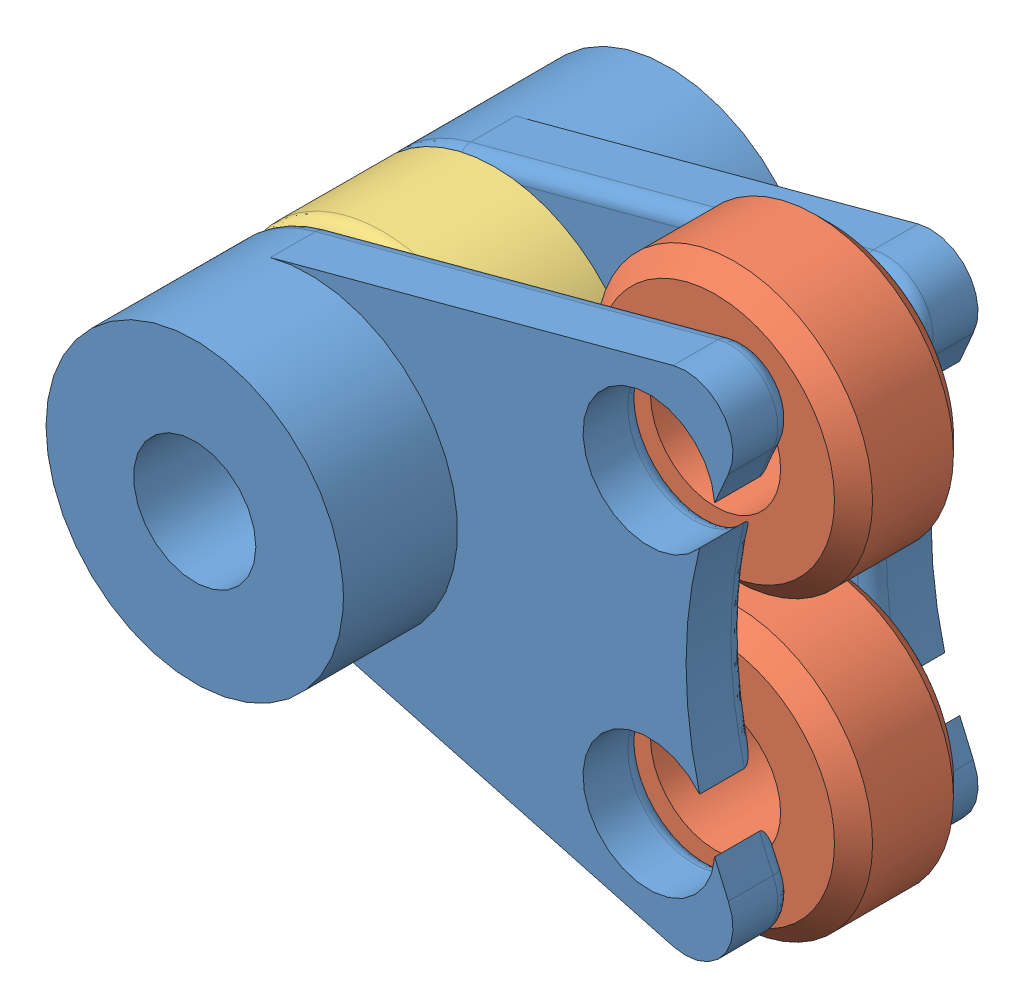
SolidWorks assembly RollerUnit, configuration Default. Lengths in mm.
Overall size (32.43 29.25 25.27).
5 component instances, 3 part files, 11 mates.
Components (placement in the parent):
- BeltRollerHolder-1: BeltRollerHolder [Default] at (6.1615 25.2155 19.6382) size (31.33 29.25 9.33)
- BeltRollerHolder-2: BeltRollerHolder [Default] at (6.1615 25.2155 32.7192) x (1 0 0) z (0 0 -1) size (31.33 29.25 9.33)
- 0.5Roller-2: 0.5Roller [Default] at (24.3085 33.153 22.8132) x (1 0 0) z (0 -1 0) size (12.7 6.35 12.7)
- 0.5Roller-3: 0.5Roller [Default] at (24.3085 17.278 22.8132) x (1 0 0) z (0 -1 0) size (12.7 6.35 12.7)
- BeltRollerHolderSpacer-1: BeltRollerHolderSpacer [Default] at (6.1615 25.2155 29.5442) x (1 0 0) z (0 1 0) size (15.88 6.73 15.88)
Mates (geometry in assembly coordinates):
- Concentric1: concentric anti-aligned: cylinder of BeltRollerHolder-2 through (25.0411 35.1495 29.3537) axis (0 0 -1) radius 1.7272; cylinder of ? through (25.0411 35.1495 28.9727) axis (0 0 1) radius 2.1526
- Concentric2: concentric anti-aligned: cylinder of BeltRollerHolder-2 through (24.3085 33.153 32.7192) axis (0 0 -1) radius 3.5179; cylinder of 0.5Roller-2 through (24.3085 33.153 29.1632) axis (0 0 1) radius 3.475
- Concentric3: concentric anti-aligned: cylinder of BeltRollerHolder-2 through (24.3085 17.278 32.7192) axis (0 0 -1) radius 3.5179; cylinder of 0.5Roller-3 through (24.3085 17.278 29.1632) axis (0 0 1) radius 3.475
- Coincident3: coincident aligned: plane of ? through (25.0411 35.1495 22.6227) normal (0 0 -1); plane of 0.5Roller-2 through (24.8758 34.7405 22.6227) normal (0 0 -1)
- Coincident4: coincident aligned: plane of 0.5Roller-2 through (24.3085 33.153 22.8132) normal (0 0 -1); plane of 0.5Roller-3 through (24.3085 17.278 22.8132) normal (0 0 -1)
- Coincident5: coincident anti-aligned: plane of BeltRollerHolder-1 through (49.024 25.2155 22.8132) normal (0 0 1); plane of 0.5Roller-3 through (24.3085 17.278 22.8132) normal (0 0 -1)
- Concentric4: concentric anti-aligned: cylinder of BeltRollerHolder-1 through (6.1615 25.2155 22.8132) axis (0 0 -1) radius 7.9375; cylinder of BeltRollerHolder-2 through (6.1615 25.2155 29.5442) axis (0 0 1) radius 7.9375
- Coincident6: coincident anti-aligned: line of BeltRollerHolder-1 through (3.4467 32.6743 22.0332) axis (0 0 -1); line of BeltRollerHolder-2 through (3.4467 32.6743 30.3242) axis (0 0 1)
- Concentric5: concentric anti-aligned: cylinder of BeltRollerHolder-2 through (6.1615 25.2155 29.5442) axis (0 0 -1) radius 3.2639; cylinder of BeltRollerHolderSpacer-1 through (6.1615 25.2155 22.8132) axis (0 0 1) radius 3.475
- Coincident7: coincident anti-aligned: plane of BeltRollerHolder-1 through (49.024 25.2155 22.8132) normal (0 0 1); plane of BeltRollerHolderSpacer-1 through (6.1615 25.2155 22.8132) normal (0 0 -1)
- Coincident8: coincident anti-aligned: plane of BeltRollerHolder-2 through (49.024 25.2155 29.5442) normal (0 0 -1); plane of BeltRollerHolderSpacer-1 through (6.1615 25.2155 29.5442) normal (0 0 1)
